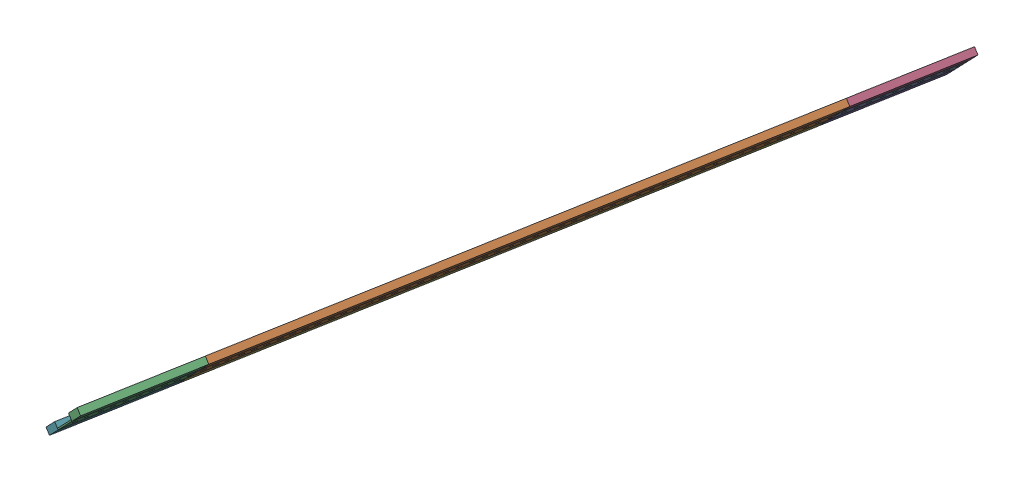
SolidWorks assembly Track_01, configuration Default. Lengths in mm.
Overall size (5788.24 3143.57 13721.89).
82 component instances, 5 part files, 24 mates.
Components (placement in the parent):
- additive_to_track-1: additive_to_track [Default] at (-2132.7381 -492.5613 4812.5663) x (0.662353 0.676347 0.322247) z (-0.322247 -0.13111 0.937532) size (800 25 2000)
- track-1: track [Default] at (-2251.786 -591.2518 4881.0958) x (-0.662353 -0.676347 -0.322247) z (0.322247 0.13111 -0.937532) size (800 25 10000)
- additive_to_track-2: additive_to_track [Default] at (-5999.7022 -2065.8806 16062.9554) x (0.662353 0.676347 0.322247) z (-0.322247 -0.13111 0.937532) size (800 25 2000)
- lane_track_01-1: lane_track_01 [Default] at (-2220.2312 -522.4305 4912.8546) x (0.662353 0.676347 0.322247) z (-0.322247 -0.13111 0.937532) size (50 25 9900)
  - lane-1: lane [Default] at (13.0249 -24.3771 9.6884) size (50 25 100)
  - lane-2: lane [Default] at (13.0249 -24.3771 209.6884) size (50 25 100)
  - lane-3: lane [Default] at (13.0249 -24.3771 409.6884) size (50 25 100)
  - lane-4: lane [Default] at (13.0249 -24.3771 609.6884) size (50 25 100)
  - lane-5: lane [Default] at (13.0249 -24.3771 809.6884) size (50 25 100)
  - lane-6: lane [Default] at (13.0249 -24.3771 1009.6884) size (50 25 100)
  - lane-7: lane [Default] at (13.0249 -24.3771 1209.6884) size (50 25 100)
  - lane-8: lane [Default] at (13.0249 -24.3771 1409.6884) size (50 25 100)
  - lane-9: lane [Default] at (13.0249 -24.3771 1609.6884) size (50 25 100)
  - lane-10: lane [Default] at (13.0249 -24.3771 1809.6884) size (50 25 100)
  - lane-11: lane [Default] at (13.0249 -24.3771 2009.6884) size (50 25 100)
  - lane-12: lane [Default] at (13.0249 -24.3771 2209.6884) size (50 25 100)
  - lane-13: lane [Default] at (13.0249 -24.3771 2409.6884) size (50 25 100)
  - lane-14: lane [Default] at (13.0249 -24.3771 2609.6884) size (50 25 100)
  - lane-15: lane [Default] at (13.0249 -24.3771 2809.6884) size (50 25 100)
  - lane-16: lane [Default] at (13.0249 -24.3771 3009.6884) size (50 25 100)
  - lane-17: lane [Default] at (13.0249 -24.3771 3209.6884) size (50 25 100)
  - lane-18: lane [Default] at (13.0249 -24.3771 3409.6884) size (50 25 100)
  - lane-19: lane [Default] at (13.0249 -24.3771 3609.6884) size (50 25 100)
  - lane-20: lane [Default] at (13.0249 -24.3771 3809.6884) size (50 25 100)
  - lane-21: lane [Default] at (13.0249 -24.3771 4009.6884) size (50 25 100)
  - lane-22: lane [Default] at (13.0249 -24.3771 4209.6884) size (50 25 100)
  - lane-23: lane [Default] at (13.0249 -24.3771 4409.6884) size (50 25 100)
  - lane-24: lane [Default] at (13.0249 -24.3771 4609.6884) size (50 25 100)
  - lane-25: lane [Default] at (13.0249 -24.3771 4809.6884) size (50 25 100)
  - lane-26: lane [Default] at (13.0249 -24.3771 5009.6884) size (50 25 100)
  - lane-27: lane [Default] at (13.0249 -24.3771 5209.6884) size (50 25 100)
  - lane-28: lane [Default] at (13.0249 -24.3771 5409.6884) size (50 25 100)
  - lane-29: lane [Default] at (13.0249 -24.3771 5609.6884) size (50 25 100)
  - lane-30: lane [Default] at (13.0249 -24.3771 5809.6884) size (50 25 100)
  - lane-31: lane [Default] at (13.0249 -24.3771 6009.6884) size (50 25 100)
  - lane-32: lane [Default] at (13.0249 -24.3771 6209.6884) size (50 25 100)
  - lane-33: lane [Default] at (13.0249 -24.3771 6409.6884) size (50 25 100)
  - lane-34: lane [Default] at (13.0249 -24.3771 6609.6884) size (50 25 100)
  - lane-35: lane [Default] at (13.0249 -24.3771 6809.6884) size (50 25 100)
  - lane-36: lane [Default] at (13.0249 -24.3771 7009.6884) size (50 25 100)
  - lane-37: lane [Default] at (13.0249 -24.3771 7209.6884) size (50 25 100)
  - lane-38: lane [Default] at (13.0249 -24.3771 7409.6884) size (50 25 100)
  - lane-39: lane [Default] at (13.0249 -24.3771 7609.6884) size (50 25 100)
  - lane-40: lane [Default] at (13.0249 -24.3771 7809.6884) size (50 25 100)
  - lane-41: lane [Default] at (13.0249 -24.3771 8009.6884) size (50 25 100)
  - lane-42: lane [Default] at (13.0249 -24.3771 8209.6884) size (50 25 100)
  - lane-43: lane [Default] at (13.0249 -24.3771 8409.6884) size (50 25 100)
  - lane-44: lane [Default] at (13.0249 -24.3771 8609.6884) size (50 25 100)
  - lane-45: lane [Default] at (13.0249 -24.3771 8809.6884) size (50 25 100)
  - lane-46: lane [Default] at (13.0249 -24.3771 9009.6884) size (50 25 100)
  - lane-47: lane [Default] at (13.0249 -24.3771 9209.6884) size (50 25 100)
  - lane-48: lane [Default] at (13.0249 -24.3771 9409.6884) size (50 25 100)
  - lane-49: lane [Default] at (13.0249 -24.3771 9609.6884) size (50 25 100)
  - lane-50: lane [Default] at (13.0249 -24.3771 9809.6884) size (50 25 100)
- lane_addetive-1: lane_addetive [Default] at (-1560.5161 -273.0553 3016.5373) x (0.662353 0.676347 0.322247) z (-0.322247 -0.13111 0.937532) size (50 25 1900)
  - lane-1: lane [Default] at (18.4792 -7.5587 32.8341) size (50 25 100)
  - lane-2: lane [Default] at (18.4792 -7.5587 232.8341) size (50 25 100)
  - lane-3: lane [Default] at (18.4792 -7.5587 432.8341) size (50 25 100)
  - lane-4: lane [Default] at (18.4792 -7.5587 632.8341) size (50 25 100)
  - lane-5: lane [Default] at (18.4792 -7.5587 832.8341) size (50 25 100)
  - lane-6: lane [Default] at (18.4792 -7.5587 1032.8341) size (50 25 100)
  - lane-7: lane [Default] at (18.4792 -7.5587 1232.8341) size (50 25 100)
  - lane-8: lane [Default] at (18.4792 -7.5587 1432.8341) size (50 25 100)
  - lane-9: lane [Default] at (18.4792 -7.5587 1632.8341) size (50 25 100)
  - lane-10: lane [Default] at (18.4792 -7.5587 1832.8341) size (50 25 100)
- lane_addetive-2: lane_addetive [Default] at (-5427.4802 -1846.3746 14266.9265) x (0.662353 0.676347 0.322247) z (-0.322247 -0.13111 0.937532) size (50 25 1900)
  - lane-1: lane [Default] at (18.4792 -7.5587 32.8341) size (50 25 100)
  - lane-2: lane [Default] at (18.4792 -7.5587 232.8341) size (50 25 100)
  - lane-3: lane [Default] at (18.4792 -7.5587 432.8341) size (50 25 100)
  - lane-4: lane [Default] at (18.4792 -7.5587 632.8341) size (50 25 100)
  - lane-5: lane [Default] at (18.4792 -7.5587 832.8341) size (50 25 100)
  - lane-6: lane [Default] at (18.4792 -7.5587 1032.8341) size (50 25 100)
  - lane-7: lane [Default] at (18.4792 -7.5587 1232.8341) size (50 25 100)
  - lane-8: lane [Default] at (18.4792 -7.5587 1432.8341) size (50 25 100)
  - lane-9: lane [Default] at (18.4792 -7.5587 1632.8341) size (50 25 100)
  - lane-10: lane [Default] at (18.4792 -7.5587 1832.8341) size (50 25 100)
- sidewalk-1: sidewalk [Default] at (-5116.7982 -1558.6319 14312.6244) x (0.662353 0.676347 0.322247) z (-0.322247 -0.13111 0.937532) size (500 125 10000)
- add_sidewalk-1: add_sidewalk [Default] at (-5469.9469 -1727.9173 15198.5206) x (0.662353 0.676347 0.322247) z (-0.322247 -0.13111 0.937532) size (500 125 2000)
- add_sidewalk-2: add_sidewalk [Default] at (-1602.9828 -154.598 3948.1314) x (0.662353 0.676347 0.322247) z (-0.322247 -0.13111 0.937532) size (500 125 2000)
- add_sidewalk-3: add_sidewalk [Default] at (-2464.0412 -1033.8497 3529.2103) x (0.662353 0.676347 0.322247) z (-0.322247 -0.13111 0.937532) size (500 125 2000)
- sidewalk-3: sidewalk [Default] at (-5977.8566 -2437.8836 13893.7033) x (0.662353 0.676347 0.322247) z (-0.322247 -0.13111 0.937532) size (500 125 10000)
- add_sidewalk-4: add_sidewalk [Default] at (-6331.0053 -2607.169 14779.5994) x (0.662353 0.676347 0.322247) z (-0.322247 -0.13111 0.937532) size (500 125 2000)
Mates (geometry in assembly coordinates):
- Coincident1: coincident anti-aligned: plane of additive_to_track-1 through (-2166.775 -481.4096 4859.1207) normal (-0.322247 -0.13111 0.937532); plane of track-1 through (-2248.587 -564.9503 4819.3176) normal (0.322247 0.13111 -0.937532)
- Coincident2: coincident aligned: plane of additive_to_track-1 through (-1923.0975 -243.1047 4919.5091) normal (0.662353 0.676347 0.322247); plane of track-1 through (-1960.3334 -258.2546 5027.8417) normal (0.662353 0.676347 0.322247)
- Coincident3: coincident aligned: plane of additive_to_track-1 through (-2149.6468 -474.4408 4809.2886) normal (-0.676347 0.72482 -0.13111); plane of track-1 through (-2268.6947 -573.1313 4877.8181) normal (-0.676347 0.72482 -0.13111)
- Coincident5: coincident anti-aligned: plane of track-1 through (-5471.0571 -1876.0497 14194.6419) normal (-0.322247 -0.13111 0.937532); plane of additive_to_track-2 through (-5389.2451 -1792.509 14234.445) normal (0.322247 0.13111 -0.937532)
- Coincident6: coincident aligned: plane of track-1 through (-2268.6947 -573.1313 4877.8181) normal (-0.676347 0.72482 -0.13111); plane of additive_to_track-2 through (-6016.6109 -2047.7601 16059.6777) normal (-0.676347 0.72482 -0.13111)
- Coincident7: coincident aligned: plane of track-1 through (-1960.3334 -258.2546 5027.8417) normal (0.662353 0.676347 0.322247); plane of additive_to_track-2 through (-5790.0615 -1816.424 16169.8982) normal (0.662353 0.676347 0.322247)
- Coincident8: coincident aligned: plane of track-1 through (-2268.6947 -573.1313 4877.8181) normal (-0.676347 0.72482 -0.13111); plane of lane_track_01-1/lane-20 through (-3439.686 -1012.6577 8488.6766) normal (-0.676347 0.72482 -0.13111)
- Coincident9: coincident anti-aligned: plane of track-1 through (-5438.8324 -1862.9387 14100.8887) normal (0.322247 0.13111 -0.937532); plane of lane_track_01-1/lane-50 through (-5411.9709 -1835.5096 14113.9573) normal (-0.322247 -0.13111 0.937532)
- Coincident10: coincident anti-aligned: plane of track-1 through (-2208.7156 -511.8849 4906.9991) normal (-0.662353 -0.676347 -0.322247); plane of lane_track_01-1/lane-50 through (-5346.6286 -1788.5813 14036.3164) normal (0.662353 0.676347 0.322247)
- Coincident11: coincident aligned: plane of additive_to_track-2 through (-6016.6109 -2047.7601 16059.6777) normal (-0.676347 0.72482 -0.13111); plane of lane_addetive-2/lane-6 through (-5759.8644 -1956.6492 15238.9101) normal (-0.676347 0.72482 -0.13111)
- Coincident12: coincident anti-aligned: plane of additive_to_track-2 through (-6001.5144 -2041.6179 16015.7566) normal (0.322247 0.13111 -0.937532); plane of lane_addetive-2/lane-10 through (-6056.4649 -2097.7295 15989.0221) normal (-0.322247 -0.13111 0.937532)
- Coincident13: coincident anti-aligned: plane of additive_to_track-2 through (-6071.5614 -2103.8717 16032.9432) normal (0.662353 0.676347 0.322247); plane of lane_addetive-2/lane-10 through (-6024.2402 -2084.6185 15895.2689) normal (-0.662353 -0.676347 -0.322247)
- Coincident14: coincident aligned: plane of additive_to_track-1 through (-2149.6468 -474.4408 4809.2886) normal (-0.676347 0.72482 -0.13111); plane of lane_addetive-1/lane-4 through (-1764.0016 -330.886 3613.508) normal (-0.676347 0.72482 -0.13111)
- Coincident15: coincident anti-aligned: plane of additive_to_track-1 through (-2134.5503 -468.2986 4765.3675) normal (0.322247 0.13111 -0.937532); plane of lane_addetive-1/lane-10 through (-2189.5008 -524.4102 4738.633) normal (-0.322247 -0.13111 0.937532)
- Coincident16: coincident anti-aligned: plane of additive_to_track-1 through (-2204.5973 -530.5524 4782.5541) normal (0.662353 0.676347 0.322247); plane of lane_addetive-1/lane-10 through (-2157.2761 -511.2992 4644.8798) normal (-0.662353 -0.676347 -0.322247)
- Coincident17: coincident anti-aligned: plane of track-1 through (-1960.3334 -258.2546 5027.8417) normal (0.662353 0.676347 0.322247); plane of sidewalk-1 through (-2007.8604 -177.5915 4956.2302) normal (-0.662353 -0.676347 -0.322247)
- Coincident18: coincident aligned: plane of track-1 through (-2251.786 -591.2518 4881.0958) normal (0.676347 -0.72482 0.13111); plane of sidewalk-1 through (-5116.7982 -1558.6319 14312.6244) normal (0.676347 -0.72482 0.13111)
- Coincident19: coincident aligned: plane of track-1 through (-5471.0571 -1876.0497 14194.6419) normal (-0.322247 -0.13111 0.937532); plane of sidewalk-1 through (-5230.3305 -1488.6909 14331.5545) normal (-0.322247 -0.13111 0.937532)
- Coincident20: coincident anti-aligned: plane of additive_to_track-2 through (-5790.0615 -1816.424 16169.8982) normal (0.662353 0.676347 0.322247); plane of add_sidewalk-1 through (-5230.3305 -1488.6909 14331.5545) normal (-0.662353 -0.676347 -0.322247)
- Coincident21: coincident aligned: plane of additive_to_track-2 through (-6033.7391 -2054.7289 16109.5098) normal (-0.322247 -0.13111 0.937532); plane of add_sidewalk-1 through (-5874.8245 -1750.9108 16206.6194) normal (-0.322247 -0.13111 0.937532)
- Coincident23: coincident aligned: plane of additive_to_track-2 through (-5999.7022 -2065.8806 16062.9554) normal (0.676347 -0.72482 0.13111); plane of add_sidewalk-1 through (-5469.9469 -1727.9173 15198.5206) normal (0.676347 -0.72482 0.13111)
- Coincident24: coincident anti-aligned: plane of additive_to_track-1 through (-1923.0975 -243.1047 4919.5091) normal (0.662353 0.676347 0.322247); plane of add_sidewalk-2 through (-1363.3664 84.6284 3081.1654) normal (-0.662353 -0.676347 -0.322247)
- Coincident25: coincident aligned: plane of additive_to_track-1 through (-1522.281 -219.1898 2984.0559) normal (0.322247 0.13111 -0.937532); plane of add_sidewalk-2 through (-1363.3664 84.6284 3081.1654) normal (0.322247 0.13111 -0.937532)
- Coincident26: coincident aligned: plane of additive_to_track-1 through (-2132.7381 -492.5613 4812.5663) normal (0.676347 -0.72482 0.13111); plane of add_sidewalk-2 through (-1602.9828 -154.598 3948.1314) normal (0.676347 -0.72482 0.13111)
